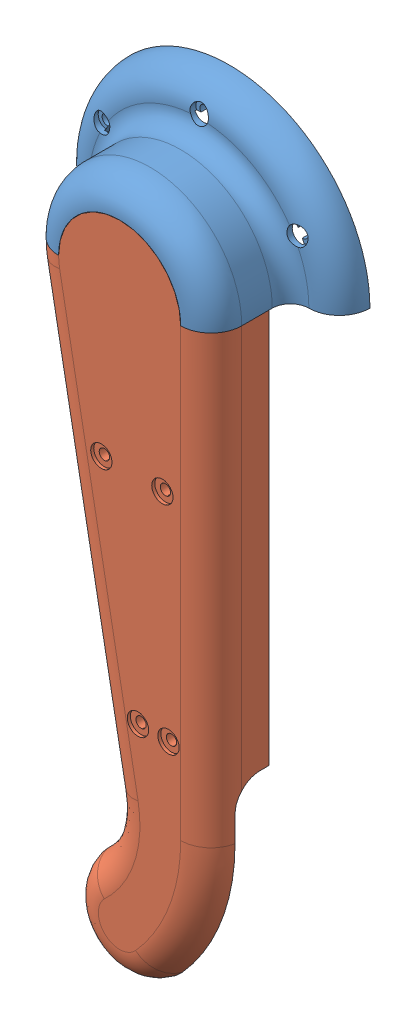
SolidWorks assembly 外壳上盖, configuration 默认. Lengths in mm.
Overall size (127.43 246 36.56).
9 component instances, 9 part files, 21 mates.
Components (placement in the parent):
- 外壳上盖1-1: 外壳上盖1 [默认] at (-20.9073 -10.7962 72) size (92 46 36)
- 外壳上盖2-1: 外壳上盖2 [默认] at (-20.9073 -10.7962 72) size (60 216.8 19.56)
- 膝关节法兰轴承-1: 膝关节法兰轴承 [默认] at (-20.9073 -190.7962 103) x (0.999154 -0.041137 0) z (0.041137 0.999154 0) size (21 5 21)
- 编码器磁钢-1: 编码器磁钢 [默认] at (-20.9073 -190.7962 101) x (1 0 0) z (0 -1 0) size (6 3 6)
- 磁编-1: 磁编 [默认] at (-20.9073 -190.7962 109) x (0.709654 -0.70455 0) z (0.70455 0.709654 0) size (15 2.35 16)
- 膝关节编码器压环-1: 膝关节编码器压环 [默认] at (-20.9073 -190.7962 104) x (0.733665 0.679512 0) z (0 0 1) size (22 22 4.4)
- 推力轴承压环-1: 推力轴承压环 [默认] at (-20.9073 -190.7962 102) x (-0.96523 -0.261403 0) z (0.261403 -0.96523 0) size (32 3 32)
- 滚针推力轴承-1: 滚针推力轴承 [默认] at (-20.9073 -190.7962 95) x (1 0 0) z (0 -1 0) size (26 4 26)
- 内侧碳板2-1: 内侧碳板2 [默认] at (9.276 -10.7962 102) x (0.95096 -0.309314 0) z (0 0 1) size (81.98 159.93 2.01)
Mates (geometry in assembly coordinates):
- 重合1: coincident anti-aligned: plane of 外壳上盖1-1 through (-20.9073 -10.7962 72) normal (0 -1 0); plane of 外壳上盖2-1 through (-20.9073 -10.7962 72) normal (0 1 0)
- 重合2: coincident aligned: circle of 外壳上盖1-1; circle of 外壳上盖2-1
- 重合3: coincident aligned: circle of 外壳上盖1-1; circle of 外壳上盖2-1
- 同心2: concentric anti-aligned: cylinder of 外壳上盖2-1 through (-20.9073 -190.7962 104) axis (0 0 -1) radius 11; cylinder of 膝关节法兰轴承-1 through (-20.9073 -190.7962 99) axis (0 0 1) radius 9.5
- 同心3: concentric anti-aligned: cylinder of 膝关节法兰轴承-1 through (-20.9073 -190.7962 104.001) axis (0 0 -1) radius 5; cylinder of 膝关节磁钢套筒-1 through (-20.9073 -190.7962 96) axis (0 0 1) radius 5
- 同心4: concentric anti-aligned: cylinder of 编码器磁钢-1 through (-20.9073 -190.7962 104) axis (0 0 -1) radius 3; cylinder of 膝关节磁钢套筒-1 through (-20.9073 -190.7962 96) axis (0 0 1) radius 3
- 重合8: coincident anti-aligned: plane of 编码器磁钢-1 through (-20.9073 -190.7962 104) normal (0 0 1); plane of 膝关节磁钢套筒-1 through (-20.9073 -190.7962 104) normal (0 0 -1)
- 同心6: concentric anti-aligned: cylinder of 外壳上盖2-1 through (-20.9073 -190.7962 104) axis (0 0 1) radius 9; cylinder of 膝关节编码器压环-1 through (-20.9073 -190.7962 108.4) axis (0 0 -1) radius 9
- 重合14: coincident anti-aligned: plane of 推力轴承压环-1 through (-20.9073 -190.7962 99) normal (0 0 -1); plane of 滚针推力轴承-1 through (-20.9073 -190.7962 99) normal (0 0 1)
- 同心8: concentric aligned: circle of 推力轴承压环-1; circle of 滚针推力轴承-1
- 重合15: coincident anti-aligned: plane of 外壳上盖2-1 through (-20.9073 -190.7962 106) normal (0 0 -1); plane of 膝关节编码器压环-1 through (-20.9073 -190.7962 106) normal (0 0 1)
- 同心9: concentric aligned: cylinder of 外壳上盖2-1 through (-16.6494 -195.0235 108) axis (0 0 1) radius 1.1; cylinder of 磁编-1 through (-16.6494 -195.0235 108.4) axis (0 0 1) radius 1.1
- 重合16: coincident anti-aligned: plane of 外壳上盖2-1 through (-20.9073 -190.7962 109) normal (0 0 -1); plane of 磁编-1 through (-20.9073 -190.7962 109) normal (0 0 1)
- 重合17: coincident anti-aligned: plane of 膝关节法兰轴承-1 through (-20.9073 -190.7962 104) normal (0 0 1); plane of 膝关节磁钢套筒-1 through (-20.9073 -190.7962 104) normal (0 0 -1)
- 重合18: coincident anti-aligned: plane of 外壳上盖2-1 through (-20.9073 -10.7962 104) normal (0 0 -1); plane of 内侧碳板2-1 through (9.276 -10.7962 104) normal (0 0 1)
- 同心10: concentric anti-aligned: circle of 外壳上盖2-1; cylinder of 内侧碳板2-1 through (-20.9073 -190.7962 104) axis (0 0 -1) radius 14.801
- 重合19: coincident anti-aligned: circle of 外壳上盖2-1; circle of 内侧碳板2-1
- 同心11: concentric anti-aligned: cylinder of 膝关节法兰轴承-1 through (-20.9073 -190.7962 99) axis (0 0 1) radius 9.5; cylinder of 内侧碳板2-1 through (-20.9073 -190.7962 104) axis (0 0 -1) radius 9.5
- 重合20: coincident anti-aligned: plane of 膝关节法兰轴承-1 through (-20.9073 -190.7962 103) normal (0 0 -1); plane of 内侧碳板2-1 through (-20.9073 -190.7962 103) normal (0 0 1)
- 同心12: concentric anti-aligned: cylinder of 膝关节法兰轴承-1 through (-20.9073 -190.7962 99) axis (0 0 1) radius 9.5; cylinder of 推力轴承压环-1 through (-20.9073 -190.7962 109) axis (0 0 -1) radius 9.5
- 重合21: coincident anti-aligned: plane of 推力轴承压环-1 through (-20.9073 -190.7962 102) normal (0 0 1); plane of 内侧碳板2-1 through (9.276 -10.7962 102) normal (0 0 -1)
